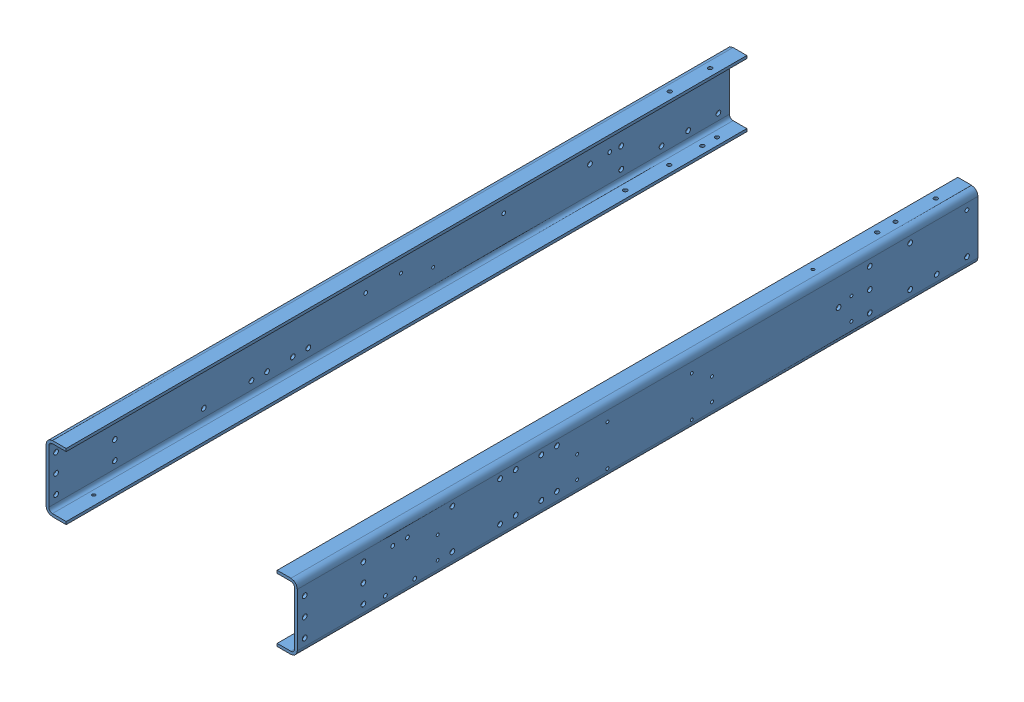
SolidWorks assembly 4307-CC1, configuration Both Rails. Lengths in mm.
Overall size (869.95 228.6 2355.85).
2 component instances, 1 part files, 6 mates.
Components (placement in the parent):
- 3623-CC1-5: 3623-CC1 [3623-CC1-92.75] at (434.975 0 901.7) size (69.85 228.6 2355.85)
- 3623-CC1-4: 3623-CC1 [3623-CC1-92.75] at (-434.975 0 -1454.15) x (-1 0 0) z (0 0 -1) size (69.85 228.6 2355.85)
Mates (geometry in assembly coordinates):
- Coincident1: coincident aligned: plane of ?; plane of assembly
- Coincident2: coincident aligned: plane of ?; plane of assembly
- Coincident3: coincident aligned: plane of ?; plane of assembly
- Coincident4: coincident anti-aligned: plane of ?; plane of assembly
- Coincident5: coincident anti-aligned: plane of ?; plane of assembly
- Coincident6: coincident aligned: 
